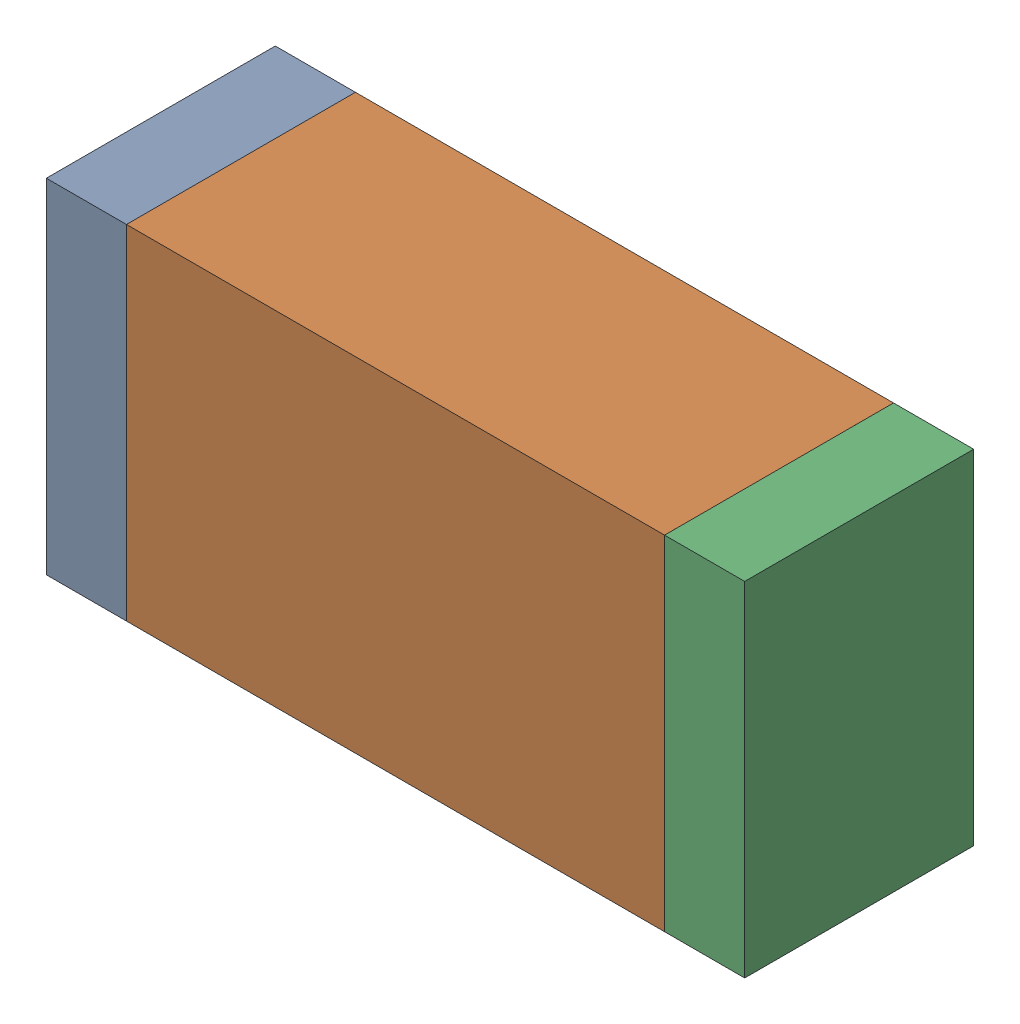
SolidWorks assembly R8, configuration Default. Lengths in mm.
Overall size (1.55 0.76 0.51).
6 component instances, 2 part files, 0 mates.
Components (placement in the parent):
- 822490216-1: 822490216 [Default] at (1.6303 2.7279 0) size (0.18 0.76 0.51)
  - Extruded-1: Extruded [Default] at origin size (0.18 0.76 0.51)
- 822498920-1: 822498920 [Default] at (2.3161 2.7279 0) size (1.19 0.76 0.51)
  - Extruded_2-1: Extruded_2 [Default] at origin size (1.19 0.76 0.51)
- 822490216-2: 822490216 [Default] at (3.0019 2.7279 0) size (0.18 0.76 0.51)
  - Extruded-1: Extruded [Default] at origin size (0.18 0.76 0.51)
